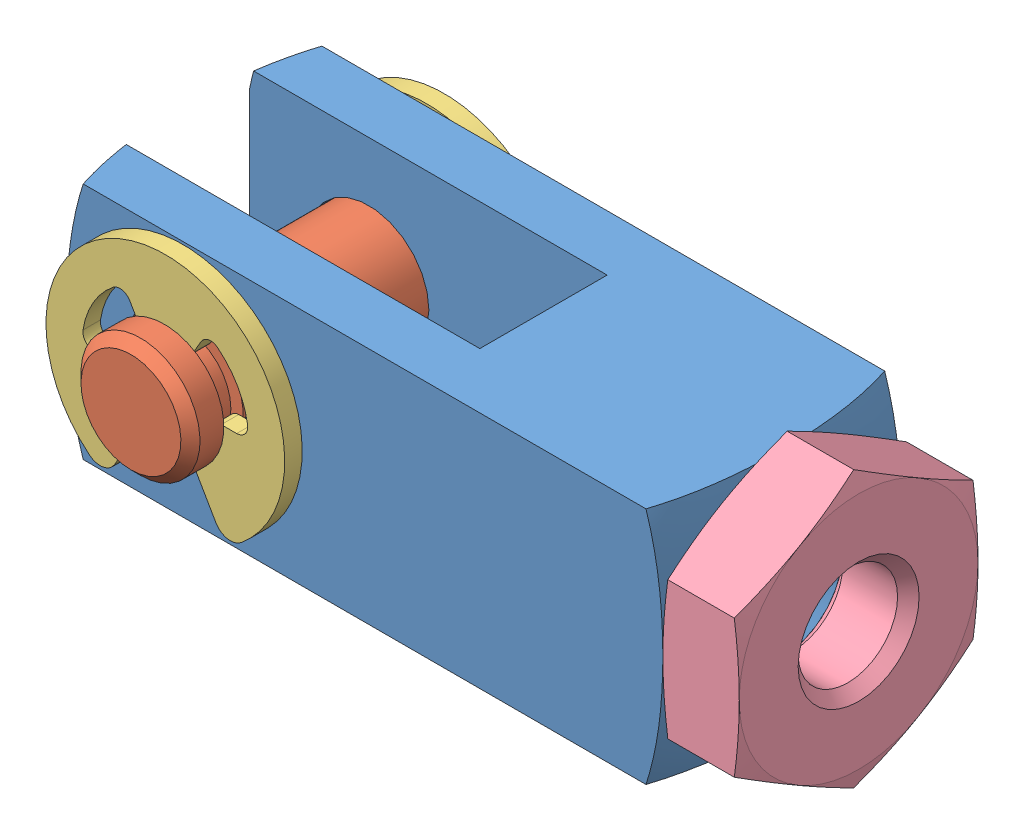
SolidWorks assembly D-850, configuration Default. Lengths in mm.
Overall size (27.67 11 13.87).
5 component instances, 4 part files, 0 mates.
Components (placement in the parent):
- _D-14043-1: _D-14043 [Default] x (1 0 0) z (0 0 -1) size (25.45 9.53 9.53)
- _D-12304-1: _D-12304 [Default] x (0 0 1) z (-1 0 0) size (13.87 4.75 4.75)
- _D-5406-1: _D-5406 [Default] at (0 0 5.2134) x (-1 0 0) z (0 0 -1) size (9.53 8.6 0.7)
- _D-5406-2: _D-5406 [Default] at (0 0 -5.2134) x (-1 0 0) z (0 0 -1) size (9.53 8.6 0.7)
- _D-5288-1: _D-5288 [Default] at (19.05 0 0) x (0 0 1) z (-1 0 0) size (9.53 11 3.05)
